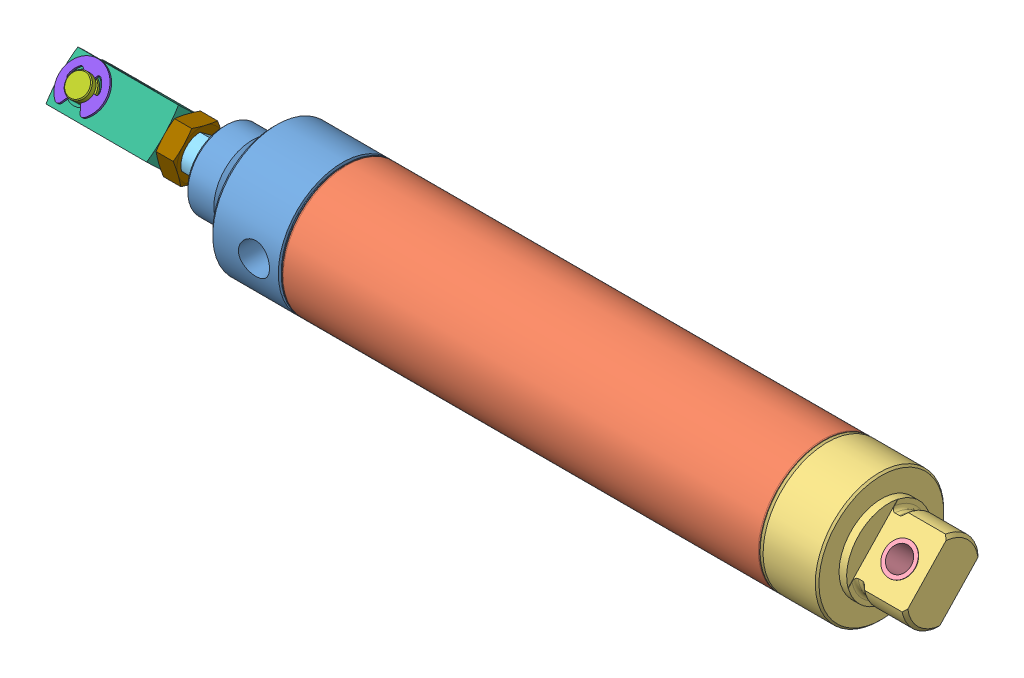
SolidWorks assembly 316-DXP_F_D-231-3__2_14, configuration Default. Lengths in mm.
Overall size (357.95 74.89 74.89).
10 component instances, 9 part files, 19 mates.
Components (placement in the parent):
- _31R000-0_rod_guide_1-1: _31R000-0_rod_guide_1 [Default] at origin size (58.72 52.97 52.97)
- _31R-7.7870_1-1: _31R-7.7870_1 [Default] at (50.2539 0 0) x (1 0 0) z (0 -0.176452 0.984309) size (199.7 52.97 52.97)
- _31P0Y000_rear_head_1-1: _31P0Y000_rear_head_1 [Default] at (241.173 0 0) x (1 0 0) z (0 -0.689467 -0.724317) size (55.58 52.97 52.97)
- _D-624-5_1-1: _D-624-5_1 [Default] at (285.623 -0.1532 -0.161) x (1 0 0) z (0 0.689467 0.724317) size (12.76 12.76 19.05)
- _316-DXP0_rod_1-1: _316-DXP0_rod_1 [Default] x (1 0 0) z (0 -0.803424 0.595407) size (272.92 51.04 51.04)
- _D-14041-1: _D-14041 [Default] at (-50.673 0 0) x (1 0 0) z (0 -0.689467 -0.724317) size (44.68 19.05 19.05)
- _D-8383-1: _D-8383 [Default] at (-50.673 -0.1138 -0.1196) x (0 0.689467 0.724317) z (-1 0 0) size (26.19 9.56 9.56)
- _D-5867-1: _D-5867 [Default] at (-50.673 6.8868 7.2349) x (-1 0 0) z (0 -0.689467 -0.724317) size (19.05 17.19 0.93)
- _D-5867-2: _D-5867 [Default] at (-50.673 -7.1144 -7.474) x (-1 0 0) z (0 -0.689467 -0.724317) size (19.05 17.19 0.93)
- _D-98-1: _D-98 [Default] at (-17.399 0 0) x (0 0.971587 -0.236681) z (-1 0 0) size (19.05 22 7.87)
Mates (geometry in assembly coordinates):
- Concentric1: concentric aligned: cylinder of _D-14041-1 through (-50.673 6.5672 6.8991) axis (0 -0.689467 -0.724317) radius 4.826; cylinder of _D-8383-1 through (-50.673 8.9138 9.3644) axis (0 -0.689467 -0.724317) radius 4.7816
- Coincident1: coincident anti-aligned: plane of _D-8383-1 through (-50.673 10.0074 4.9044) normal (0 -0.689467 -0.724317); plane of _D-5867-1 through (-55.8707 2.6265 11.9301) normal (0 0.689467 0.724317)
- Concentric2: concentric aligned: cylinder of _D-8383-1 through (-50.673 8.9138 9.3644) axis (0 -0.689467 -0.724317) radius 4.7816; cylinder of _D-5867-1 through (-50.673 6.5672 6.8991) axis (0 -0.689467 -0.724317) radius 9.525
- Coincident2: coincident anti-aligned: plane of _D-8383-1 through (-50.673 -3.9707 -11.1065) normal (0 0.689467 0.724317); plane of _D-5867-2 through (-55.8707 -12.0139 -3.4503) normal (0 -0.689467 -0.724317)
- Concentric3: concentric aligned: cylinder of _D-8383-1 through (-50.673 8.9138 9.3644) axis (0 -0.689467 -0.724317) radius 4.7816; cylinder of _D-5867-2 through (-50.673 -7.434 -7.8098) axis (0 -0.689467 -0.724317) radius 9.525
- Coincident3: coincident anti-aligned: plane of _D-14041-1 through (-50.673 6.5672 6.8991) normal (0 0.689467 0.724317); plane of _D-5867-1 through (-55.8707 1.9873 11.2586) normal (0 -0.689467 -0.724317)
- Concentric5: concentric aligned: cylinder of _316-DXP0_rod_1-1 through (-9.525 0 0) axis (-1 0 0) radius 6.35; cylinder of _D-14041-1 through (-17.399 0 0) axis (-1 0 0) radius 5.6629
- Concentric6: concentric aligned: cylinder of _316-DXP0_rod_1-1 through (-9.525 0 0) axis (-1 0 0) radius 6.35; cylinder of _D-98-1 through (-9.525 0 0) axis (-1 0 0) radius 5.6629
- Concentric7: concentric aligned: cylinder of _31R000-0_rod_guide_1-1 through (58.7248 0 0) axis (-1 0 0) radius 8.0074; cylinder of _316-DXP0_rod_1-1 through (241.173 0 0) axis (-1 0 0) radius 7.9375
- Concentric8: concentric aligned: cylinder of _31R000-0_rod_guide_1-1 through (58.7248 0 0) axis (-1 0 0) radius 26.4858; cylinder of _31R-7.7870_1-1 through (248.0437 0 0) axis (-1 0 0) radius 26.4858
- Concentric9: concentric aligned: cylinder of _31R-7.7870_1-1 through (248.0437 0 0) axis (-1 0 0) radius 26.4858; cylinder of _31P0Y000_rear_head_1-1 through (271.3736 0 0) axis (-1 0 0) radius 26.4858
- Coincident4: coincident aligned: cone of _31R-7.7870_1-1 through (247.8747 0 0) axis (1 0 0); cone of _31P0Y000_rear_head_1-1 through (247.6501 0 0) axis (1 0 0)
- Concentric10: concentric aligned: circle of _31P0Y000_rear_head_1-1; cylinder of _D-624-5_1-1 through (285.623 -6.7204 -7.0601) axis (0 0.689467 0.724317) radius 4.7879
- Distance1: distance = 0.635 mm aligned: plane of _D-624-5_1-1 through (285.623 -3.2525 -10.3612) normal (0 -0.689467 -0.724317); plane of _31P0Y000_rear_head_1-1 through (274.4978 -44.6509 29.9221) normal (0 -0.689467 -0.724317)
- Coincident6: coincident anti-aligned: plane of _316-DXP0_rod_1-1 through (-9.525 0 0) normal (-1 0 0); plane of _D-98-1 through (-9.525 -2.2544 -9.2544) normal (1 0 0)
- Coincident7: coincident anti-aligned: plane of _D-14041-1 through (-17.399 0.3319 -13.4663) normal (1 0 0); plane of _D-98-1 through (-17.399 0 0) normal (-1 0 0)
- LimitDistance1: limit distance = 152.4 mm anti-aligned: plane of _316-DXP0_rod_1-1 through (211.1248 4.726 6.3772) normal (-1 0 0); plane of _31R000-0_rod_guide_1-1 through (58.7248 24.8095 0) normal (1 0 0)
- Coincident8: coincident aligned: cone of _31R000-0_rod_guide_1-1 through (50.6475 0 0) axis (-1 0 0); cone of _31R-7.7870_1-1 through (50.4229 0 0) axis (-1 0 0)
- Parallel1: parallel anti-aligned: plane of _31P0Y000_rear_head_1-1 through (274.4978 -44.6509 29.9221) normal (0 -0.689467 -0.724317); plane of _D-14041-1 through (-50.673 6.5672 6.8991) normal (0 0.689467 0.724317)
